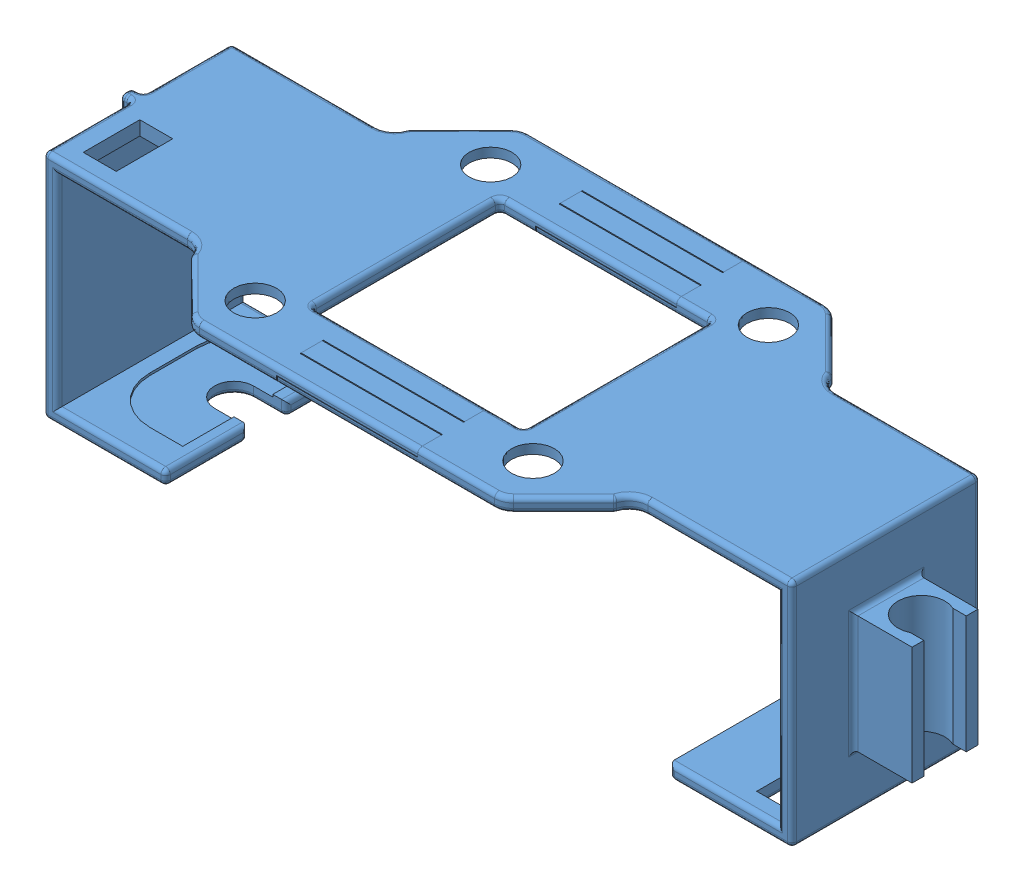
SolidWorks assembly Assem1, configuration Default. Lengths in mm.
Overall size (174 56.5 70).
2 component instances, 2 part files, 0 mates.
Components (placement in the parent):
- Part1-1: Part1 [Default] at (32.2218 30.8198 58.1145) size (79 24 70) (hidden)
- Protype 6 with dampner-1: Protype 6 with dampner [Default] at (32.2357 40.7532 58.3381) size (174 56.5 70)
